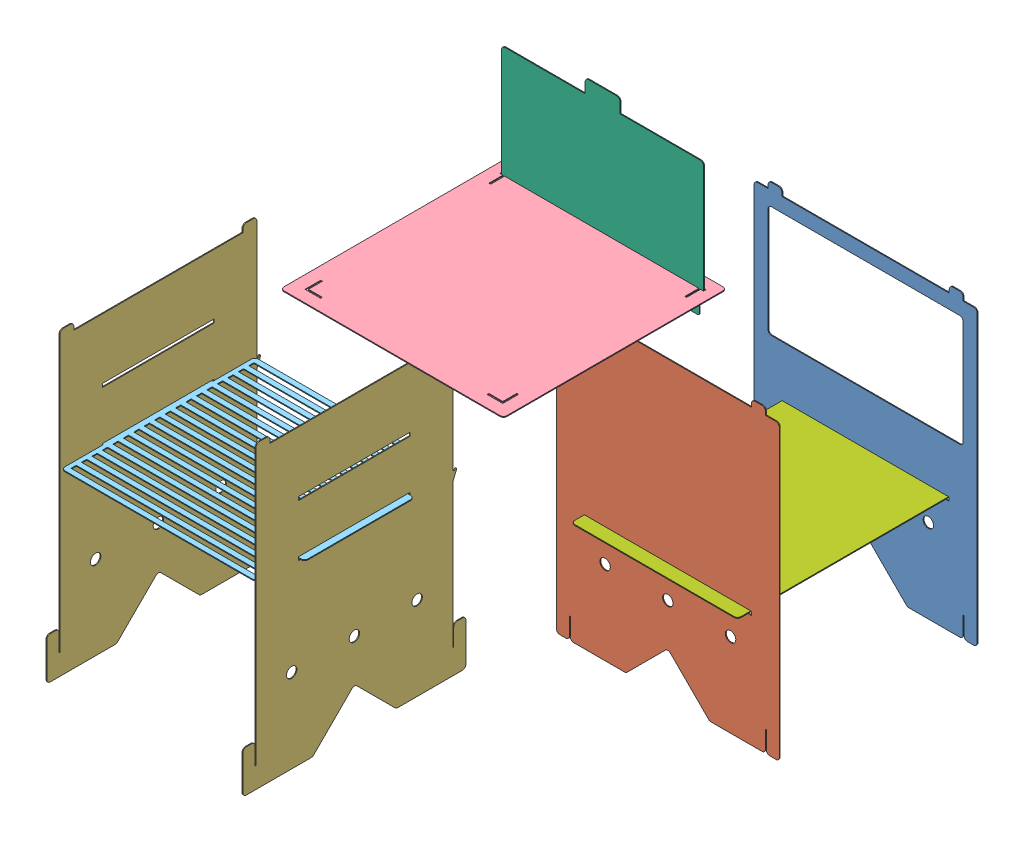
SolidWorks assembly Assembly, configuration Default. Lengths in mm.
Overall size (401.07 462.36 463.7).
8 component instances, 7 part files, 7 mates.
Components (placement in the parent):
- Front-1: Front [Default] at (516.6928 -119.5617 -291.887) size (203.2 273.05 0.79)
- Back-1: Back [Default] at (301.5868 -119.5617 -111.7057) size (203.2 273.05 0.79)
- Side-1: Side [Default] at (649.8314 -119.5617 739.6084) x (0 0 -1) z (1 0 0) size (203.2 273.05 0.79)
- Side-2: Side [Default] at (471.2377 -119.5617 739.6084) x (0 0 -1) z (1 0 0) size (203.2 273.05 0.79)
- Top-1: Top [Default] at (965.1343 662.2609 -332.5156) x (-1 0 0) z (0 1 0) size (203.2 203.2 0.79)
- Rack-1: Rack [Default] at (241.1474 477.2165 -842.9465) x (0 0 1) z (0 1 0) size (176.21 189.71 0.79)
- Door-1: Door [Default] at (-186.0679 75.4216 -100.3675) size (184.15 135.7 0.79)
- Diffuser-1: Diffuser [Default] at (415.9507 419.7707 -664.1436) x (0 0 1) z (0 1 0) size (203.2 151.61 0.79)
Mates (geometry in assembly coordinates):
- Coincident2: coincident aligned: plane of Front-1 through (850.9803 314.818 -291.0932) normal (0 -1 0); plane of Back-1 through (676.3553 314.818 -110.912) normal (0 -1 0)
- Distance2: distance = 180.975 mm anti-aligned: plane of Front-1 through (679.5303 317.993 -291.887) normal (0 0 -1); plane of Back-1 through (663.6553 581.518 -110.912) normal (0 0 1)
- Coincident4: coincident aligned: plane of Front-1 through (663.6553 578.343 -291.0932) normal (-1 0 0); plane of Back-1 through (663.6553 581.518 -110.912) normal (-1 0 0)
- Distance3: distance = 177.8 mm anti-aligned: plane of Side-1 through (649.8314 352.901 -33.6372) normal (-1 0 0); plane of Side-2 through (472.0314 352.901 -33.6372) normal (1 0 0)
- Coincident6: coincident aligned: plane of Side-1 through (650.6252 314.818 158.4503) normal (0 -1 0); plane of Side-2 through (472.0314 314.818 158.4503) normal (0 -1 0)
- Coincident7: coincident aligned: plane of Side-1 through (650.6252 467.8134 -29.6685) normal (0 0 -1); plane of Side-2 through (472.0314 467.8134 -29.6685) normal (0 0 -1)
- Coincident8: coincident aligned: plane of Front-1 through (679.5303 314.818 -291.0932) normal (0 -1 0); plane of Side-2 through (472.0314 314.818 20.6101) normal (0 -1 0)
